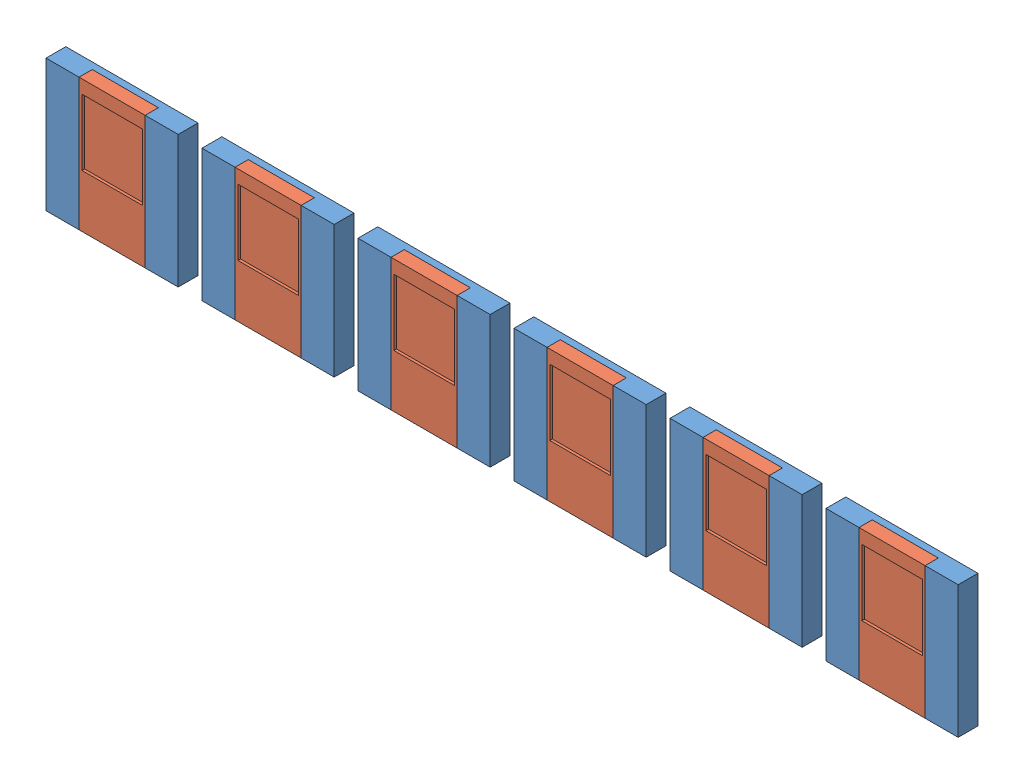
SolidWorks assembly Assem, configuration Default. Lengths in mm.
Overall size (690 100 15).
18 component instances, 2 part files, 16 mates.
Components (placement in the parent):
- part-1: part [Default] at (0.2234 51.5038 96.8009) size (100 100 15)
  - substrate-1: substrate [Default] at (23.888 54.2226 82.4663) size (100 100 15)
  - antenna-2: antenna [Default] at (23.888 69.2226 97.4663) x (-1 0 0) z (0 0 -1) size (50 100 10)
- part-2: part [Default] at (118.2234 51.5038 96.8009) size (100 100 15)
  - substrate-1: substrate [Default] at (23.888 54.2226 82.4663) size (100 100 15)
  - antenna-2: antenna [Default] at (23.888 69.2226 97.4663) x (-1 0 0) z (0 0 -1) size (50 100 10)
- part-3: part [Default] at (-117.7766 51.5038 96.8009) size (100 100 15)
  - substrate-1: substrate [Default] at (23.888 54.2226 82.4663) size (100 100 15)
  - antenna-2: antenna [Default] at (23.888 69.2226 97.4663) x (-1 0 0) z (0 0 -1) size (50 100 10)
- part-4: part [Default] at (236.2234 51.5038 96.8009) size (100 100 15)
  - substrate-1: substrate [Default] at (23.888 54.2226 82.4663) size (100 100 15)
  - antenna-2: antenna [Default] at (23.888 69.2226 97.4663) x (-1 0 0) z (0 0 -1) size (50 100 10)
- part-5: part [Default] at (-235.7766 51.5038 96.8009) size (100 100 15)
  - substrate-1: substrate [Default] at (23.888 54.2226 82.4663) size (100 100 15)
  - antenna-2: antenna [Default] at (23.888 69.2226 97.4663) x (-1 0 0) z (0 0 -1) size (50 100 10)
- part-6: part [Default] at (354.2234 51.5038 96.8009) size (100 100 15)
  - substrate-1: substrate [Default] at (23.888 54.2226 82.4663) size (100 100 15)
  - antenna-2: antenna [Default] at (23.888 69.2226 97.4663) x (-1 0 0) z (0 0 -1) size (50 100 10)
Mates (geometry in assembly coordinates):
- Coincident2: coincident aligned: plane of part-1/substrate-1 through (-25.8886 155.7264 194.2672) normal (0 1 0); plane of part-2/substrate-1 through (92.1114 155.7264 194.2672) normal (0 1 0)
- Coincident3: coincident aligned: plane of part-1/substrate-1 through (24.1114 105.7264 194.2672) normal (0 0 1); plane of part-2/substrate-1 through (142.1114 105.7264 194.2672) normal (0 0 1)
- Distance1: distance = 18 mm anti-aligned: plane of part-2/substrate-1 through (92.1114 155.7264 194.2672) normal (-1 0 0); plane of part-1/substrate-1 through (74.1114 155.7264 194.2672) normal (1 0 0)
- Coincident7: coincident aligned: plane of part-1/substrate-1 through (-25.8886 155.7264 194.2672) normal (0 1 0); plane of part-3/substrate-1 through (-143.8886 155.7264 194.2672) normal (0 1 0)
- Distance2: distance = 18 mm anti-aligned: plane of part-3/substrate-1 through (-43.8886 155.7264 194.2672) normal (1 0 0); plane of part-1/substrate-1 through (-25.8886 155.7264 194.2672) normal (-1 0 0)
- Coincident9: coincident aligned: plane of part-1/substrate-1 through (24.1114 105.7264 194.2672) normal (0 0 1); plane of part-3/substrate-1 through (-93.8886 105.7264 194.2672) normal (0 0 1)
- Coincident10: coincident aligned: plane of part-2/substrate-1 through (142.1114 105.7264 194.2672) normal (0 0 1); plane of part-4/substrate-1 through (260.1114 105.7264 194.2672) normal (0 0 1)
- Coincident11: coincident aligned: plane of part-2/substrate-1 through (142.1114 105.7264 194.2672) normal (0 0 1); plane of part-5/substrate-1 through (-211.8886 105.7264 194.2672) normal (0 0 1)
- Coincident12: coincident aligned: plane of part-1/substrate-1 through (-25.8886 155.7264 194.2672) normal (0 1 0); plane of part-5/substrate-1 through (-261.8886 155.7264 194.2672) normal (0 1 0)
- Distance3: distance = 18 mm anti-aligned: plane of part-3/substrate-1 through (-143.8886 155.7264 194.2672) normal (-1 0 0); plane of part-5/substrate-1 through (-161.8886 155.7264 194.2672) normal (1 0 0)
- Distance4: distance = 18 mm anti-aligned: plane of part-2/substrate-1 through (192.1114 155.7264 194.2672) normal (1 0 0); plane of part-4/substrate-1 through (210.1114 155.7264 194.2672) normal (-1 0 0)
- Coincident15: coincident aligned: plane of part-2/substrate-1 through (142.1114 105.7264 194.2672) normal (0 0 1); plane of part-4/substrate-1 through (260.1114 105.7264 194.2672) normal (0 0 1)
- Coincident16: coincident aligned: plane of part-2/substrate-1 through (92.1114 155.7264 194.2672) normal (0 1 0); plane of part-4/substrate-1 through (210.1114 155.7264 194.2672) normal (0 1 0)
- Distance5: distance = 18 mm anti-aligned: plane of part-4/substrate-1 through (310.1114 155.7264 194.2672) normal (1 0 0); plane of part-6/substrate-1 through (328.1114 155.7264 194.2672) normal (-1 0 0)
- Coincident18: coincident aligned: plane of part-4/substrate-1 through (210.1114 155.7264 194.2672) normal (0 1 0); plane of part-6/substrate-1 through (328.1114 155.7264 194.2672) normal (0 1 0)
- Coincident19: coincident aligned: plane of part-4/substrate-1 through (260.1114 105.7264 194.2672) normal (0 0 1); plane of part-6/substrate-1 through (378.1114 105.7264 194.2672) normal (0 0 1)
